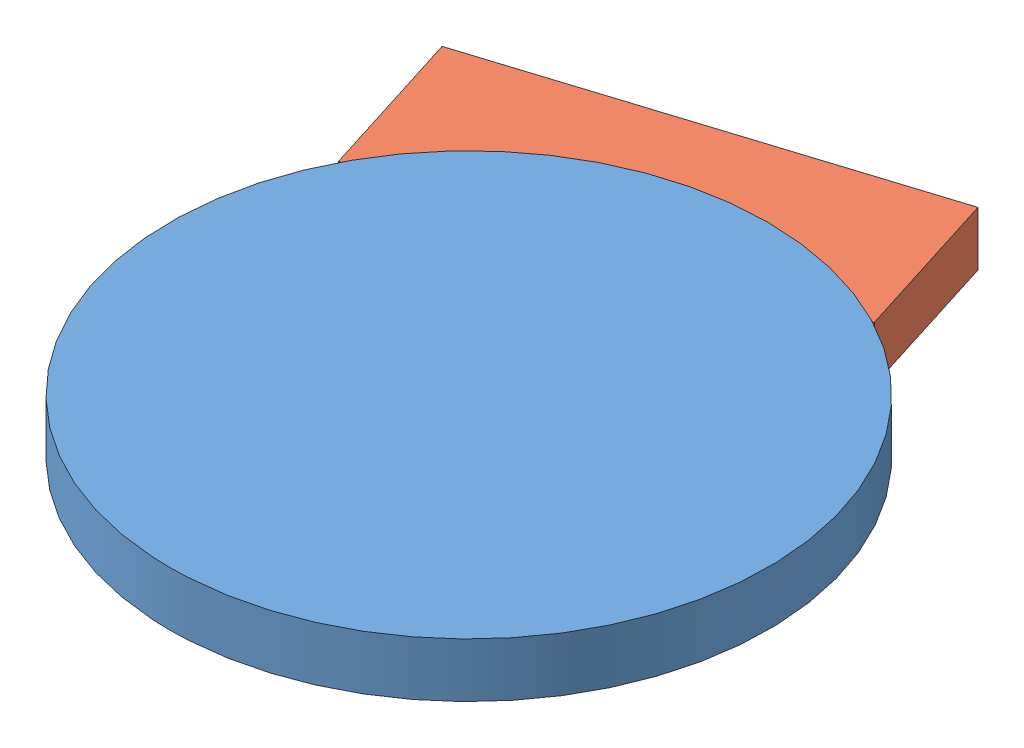
SolidWorks assembly Assem1, configuration Default. Lengths in mm.
Overall size (71.89 6.35 83.81).
2 component instances, 2 part files, 2 mates.
Components (placement in the parent):
- Part3-1: Part3 [Default] at origin size (70 6.35 70)
- Part2-1: Part2 [Default] at (-31.2949 0 -16.0226) x (0.953655 0 -0.300902) z (0.300902 0 0.953655) size (50 6.35 18.6)
Mates (geometry in assembly coordinates):
- Coincident1: coincident: line of Part3-1 through (-31.0825 6.35 -16.0896) axis (0.953655 0 -0.300902); line of Part2-1 through (-31.2949 6.35 -16.0226) axis (0.953655 0 -0.300902)
- Coincident2: coincident: plane of Part3-1 through (0 0 0) normal (0 -1 0); plane of Part2-1 through (-31.2949 0 -16.0226) normal (0 -1 0)
